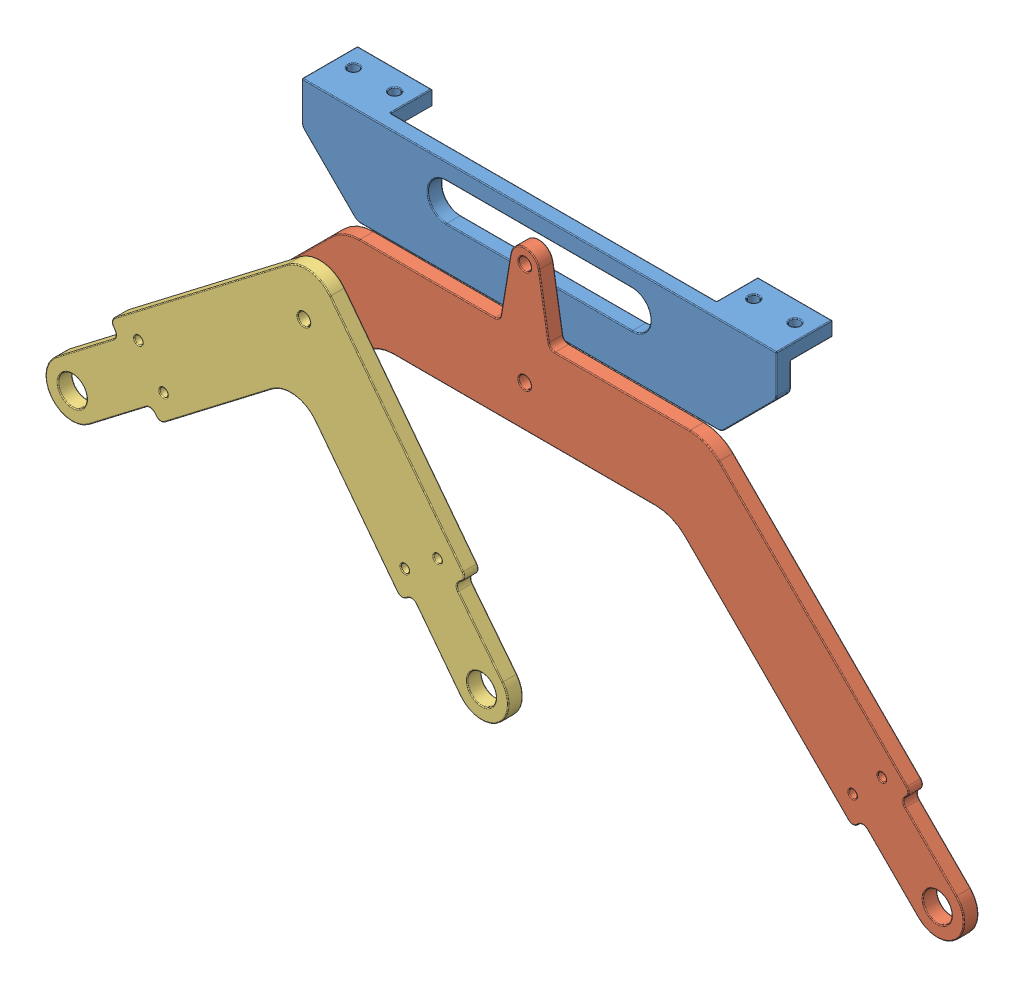
SolidWorks assembly Left rocker bogie, configuration Default. Lengths in mm.
Overall size (219.92 106.73 20.5).
3 component instances, 3 part files, 5 mates.
Components (placement in the parent):
- PLATFORM BASE-1: PLATFORM BASE [Default] at origin size (115 37.36 13.5)
- Rocker-1: Rocker [Default] at (-0.0373 0 7) x (1 -0.000622 0) z (0 0 1) size (169.47 94.85 3.5)
- BOGIE-1: BOGIE [Default] at (-6.9697 -6.0747 10.5) x (0.991423 -0.130692 0) z (0 0 1) size (113 67.54 3.5)
Mates (geometry in assembly coordinates):
- Coincident2: coordinate: point of PLATFORM BASE-1; point of assembly
- Concentric1: concentric: cylinder of PLATFORM BASE-1 through (0 60 3.5) axis (0 0 -1) radius 1.5; cylinder of Rocker-1 through (0 60 3.5) axis (0 0 1) radius 1.5
- Coincident3: coincident: plane of PLATFORM BASE-1 through (0 60 3.5) normal (0 0 1); plane of Rocker-1 through (0.0155 84.85 3.5) normal (0 0 -1)
- Concentric2: concentric: cylinder of Rocker-1 through (-50.0062 50.0311 3.5) axis (0 0 1) radius 1.5; cylinder of BOGIE-1 through (-50.0062 50.0311 7) axis (0 0 1) radius 1.5
- Coincident4: coincident: plane of Rocker-1 through (0.0155 84.85 7) normal (0 0 1); plane of BOGIE-1 through (-6.9697 -6.0747 7) normal (0 0 -1)
